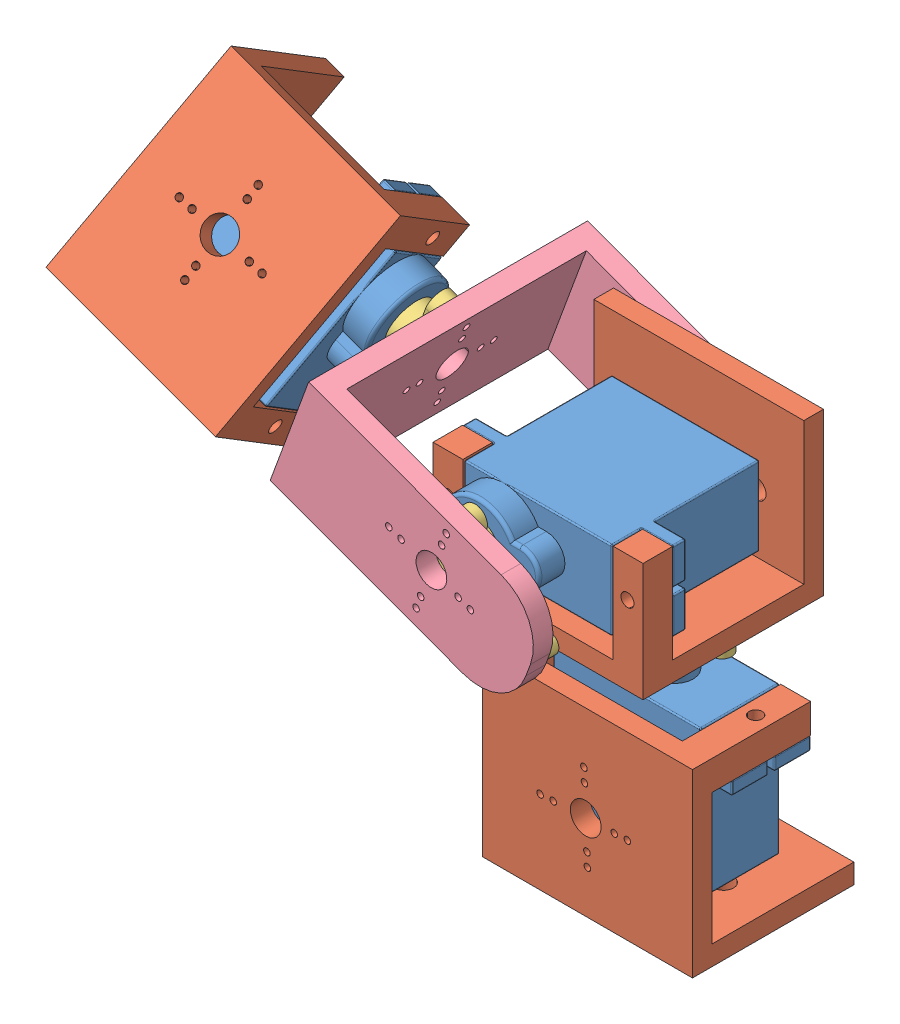
SolidWorks assembly Assem1, configuration Default. Lengths in mm.
Overall size (89.47 82.62 43.13).
10 component instances, 4 part files, 32 mates.
Components (placement in the parent):
- ServoMotor-1: ServoMotor [Valor predeterminado] at (8.0384 16.6646 27.6667) size (32 29 12)
- Body_Bracket-1: Body_Bracket [Default] at (-47.5997 31.1646 40.4918) size (32 24.6 27.5)
- Tower pro micro servo SG90 HORN-1: Tower pro micro servo SG90 HORN [Varsayılan] at (2.7884 29.6646 27.6667) x (0.999158 0 0.041036) z (-0.041036 0 0.999158) size (34.3 4 16.6)
- ServoMotor-2: ServoMotor [Valor predeterminado] at (3.0593 43.1646 35.7218) x (1 0 0) z (0 -1 0) size (32 29 12)
- Head_Bracket-1: Head_Bracket [Default] at (4.3424 15.0129 50.2218) x (0.938532 -0.345191 0) z (0 0 1) size (38.75 16.96 42.5)
- Tower pro micro servo SG90 HORN-2: Tower pro micro servo SG90 HORN [Varsayılan] at (-2.1907 43.1646 48.7218) x (0.935017 -0.354604 0) z (-0.354604 -0.935017 0) size (34.3 4 16.6)
- Tower pro micro servo SG90 HORN-3: Tower pro micro servo SG90 HORN [Varsayılan] at (-25.0551 51.6993 31.4226) x (0 0 -1) z (-0.345191 -0.938532 0) size (34.3 4 16.6)
- ServoMotor-3: ServoMotor [Valor predeterminado] at (-38.6969 52.2692 34.6068) x (-0.274451 -0.746199 0.606517) z (0.209364 0.569236 0.79507) size (32 29 12)
- Body_Bracket-3: Body_Bracket [Default] at (-42.6206 21.4346 39.6667) x (1 0 0) z (0 1 0) size (32 24.6 27.5)
- Body_Bracket-4: Body_Bracket [Default] at (-17.8043 95.2552 13.4221) x (-0.274451 -0.746199 0.606517) z (0.938532 -0.345191 0) size (32 24.6 27.5)
Mates (geometry in assembly coordinates):
- Concentric1: concentric anti-aligned: cylinder of ServoMotor-1 through (2.7884 29.6646 27.6667) axis (0 -1 0) radius 2.25; cylinder of Tower pro micro servo SG90 HORN-1 through (2.7884 27.1646 27.6667) axis (0 1 0) radius 2.3
- Coincident2: coincident anti-aligned: plane of ServoMotor-1 through (2.7884 27.1646 27.6667) normal (0 1 0); plane of Tower pro micro servo SG90 HORN-1 through (2.7884 27.1646 27.6667) normal (0 -1 0)
- Coincident3: coincident anti-aligned: plane of Body_Bracket-1 through (-47.5997 31.1646 40.4918) normal (0 -1 0); plane of Tower pro micro servo SG90 HORN-1 through (2.7884 31.1646 27.6667) normal (0 1 0)
- Distance1: distance = 3 mm anti-aligned: plane of ServoMotor-2 through (-8.1907 37.1646 19.7218) normal (0 -1 0); plane of Body_Bracket-1 through (-47.5997 34.1646 40.4918) normal (0 1 0)
- Distance2: distance = 5 mm aligned: plane of ServoMotor-2 through (3.0593 43.1646 19.7218) normal (0 0 -1); plane of Body_Bracket-1 through (19.0593 41.1646 14.7218) normal (0 0 -1)
- Coincident6: coincident aligned: plane of Body_Bracket-1 through (19.0593 41.1646 40.4918) normal (1 0 0); plane of ServoMotor-2 through (19.0593 49.1646 37.7218) normal (1 0 0)
- Concentric2: concentric aligned: cylinder of ServoMotor-2 through (-2.1907 43.1646 48.7218) axis (0 0 -1) radius 2.25; circle of Tower pro micro servo SG90 HORN-2
- Coincident7: coincident anti-aligned: plane of ServoMotor-2 through (-2.1907 43.1646 46.2218) normal (0 0 1); plane of Tower pro micro servo SG90 HORN-2 through (-2.1907 43.1646 46.2218) normal (0 0 -1)
- Tangent3: tangent aligned: plane of Head_Bracket-1 through (4.3424 15.0129 53.2218) normal (0.938532 -0.345191 0); cylinder of Tower pro micro servo SG90 HORN-2 through (11.2268 38.0761 50.2218) axis (0 0 -1) radius 1.5
- Coincident8: coincident anti-aligned: plane of Head_Bracket-1 through (-32.0298 28.3905 50.2218) normal (-0.938532 0.345191 0); plane of Tower pro micro servo SG90 HORN-3 through (-23.6473 51.1815 31.4226) normal (0.938532 -0.345191 0)
- Coincident10: coincident anti-aligned: plane of Head_Bracket-1 through (4.3424 15.0129 50.2218) normal (0 0 -1); plane of Tower pro micro servo SG90 HORN-2 through (-2.1907 43.1646 50.2218) normal (0 0 1)
- Parallel3: parallel aligned: plane of ServoMotor-1 through (-3.2116 0.6646 33.6667) normal (0 0 1); plane of Body_Bracket-1 through (3.0593 43.1646 42.2218) normal (0 0 1)
- Parallel4: parallel aligned: plane of ServoMotor-1 through (-3.2116 0.6646 33.6667) normal (0 0 1); plane of Body_Bracket-1 through (3.0593 43.1646 42.2218) normal (0 0 1)
- Concentric7: concentric anti-aligned: circle of Body_Bracket-1; circle of Tower pro micro servo SG90 HORN-1
- Concentric8: concentric aligned: circle of Body_Bracket-1; cylinder of Tower pro micro servo SG90 HORN-1 through (7.1347 31.1646 27.8452) axis (0 -1 0) radius 0.5
- Concentric11: concentric aligned: circle of Head_Bracket-1; cylinder of Tower pro micro servo SG90 HORN-2 through (0.061 49.102 50.2218) axis (0 0 -1) radius 0.5
- Concentric12: concentric anti-aligned: circle of Head_Bracket-1; circle of Tower pro micro servo SG90 HORN-2
- Tangent12: tangent aligned: plane of Head_Bracket-1 through (-17.1489 57.2621 150.2218) normal (0.345191 0.938532 0); cylinder of Tower pro micro servo SG90 HORN-3 through (-21.5589 56.8596 31.4226) axis (-0.938532 0.345191 0) radius 1.9
- Coincident11: coincident anti-aligned: plane of Tower pro micro servo SG90 HORN-3 through (-25.0551 51.6993 31.4226) normal (-0.938532 0.345191 0); plane of ServoMotor-3 through (-25.0551 51.6993 31.4226) normal (0.938532 -0.345191 0)
- Concentric14: concentric aligned: circle of Tower pro micro servo SG90 HORN-3; cylinder of ServoMotor-3 through (-25.0551 51.6993 31.4226) axis (-0.938532 0.345191 0) radius 2.25
- Concentric15: concentric aligned: cylinder of Head_Bracket-1 through (-8.3158 52.3085 31.4226) axis (-0.938532 0.345191 0) radius 0.5; cylinder of Tower pro micro servo SG90 HORN-3 through (-21.4553 57.1412 31.4226) axis (-0.938532 0.345191 0) radius 0.5
- Concentric16: concentric aligned: cylinder of Head_Bracket-1 through (-10.5078 46.3488 36.3726) axis (-0.938532 0.345191 0) radius 0.5; cylinder of Tower pro micro servo SG90 HORN-3 through (-23.6473 51.1815 36.3726) axis (-0.938532 0.345191 0) radius 0.5
- Concentric17: concentric aligned: cylinder of Head_Bracket-1 through (-6.8191 44.9199 64.2218) axis (0 0 -1) radius 0.5; cylinder of Tower pro micro servo SG90 HORN-2 through (-6.8191 44.9199 50.2218) axis (0 0 -1) radius 0.5
- Concentric18: concentric aligned: cylinder of Head_Bracket-1 through (-0.6482 47.2319 64.2218) axis (0 0 -1) radius 0.5; cylinder of Tower pro micro servo SG90 HORN-2 through (-0.6482 47.2319 50.2218) axis (0 0 -1) radius 0.5
- Concentric19: concentric aligned: cylinder of Body_Bracket-1 through (-4.1557 41.1646 27.3815) axis (0 -1 0) radius 0.5; cylinder of Tower pro micro servo SG90 HORN-1 through (-4.1557 31.1646 27.3815) axis (0 -1 0) radius 0.5
- Concentric20: concentric aligned: cylinder of Body_Bracket-1 through (2.5996 41.1646 32.2629) axis (0 -1 0) radius 0.5; cylinder of Tower pro micro servo SG90 HORN-1 through (2.5996 31.1646 32.2629) axis (0 -1 0) radius 0.5
- Concentric23: concentric aligned: cylinder of ServoMotor-1 through (-5.5866 18.6646 27.6667) axis (0 -1 0) radius 1; cylinder of Body_Bracket-3 through (-5.5866 28.6646 27.6667) axis (0 -1 0) radius 1
- Concentric24: concentric aligned: cylinder of ServoMotor-1 through (21.6634 18.6646 27.6667) axis (0 -1 0) radius 1; cylinder of Body_Bracket-3 through (21.6634 28.6646 27.6667) axis (0 -1 0) radius 1
- Coincident13: coincident anti-aligned: plane of ServoMotor-1 through (21.6634 18.6646 27.6667) normal (0 1 0); plane of Body_Bracket-3 through (-5.5866 18.6646 27.6667) normal (0 -1 0)
- Concentric25: concentric aligned: cylinder of ServoMotor-3 through (-33.0804 61.7458 26.343) axis (-0.938532 0.345191 0) radius 1; cylinder of Body_Bracket-4 through (-23.6951 58.2939 26.343) axis (-0.938532 0.345191 0) radius 1
- Concentric26: concentric aligned: cylinder of ServoMotor-3 through (-40.5592 41.4119 42.8706) axis (-0.938532 0.345191 0) radius 1; cylinder of Body_Bracket-4 through (-31.1739 37.96 42.8706) axis (-0.938532 0.345191 0) radius 1
- Coincident14: coincident anti-aligned: plane of ServoMotor-3 through (-33.0804 61.7458 26.343) normal (0.938532 -0.345191 0); plane of Body_Bracket-4 through (-33.0804 61.7458 26.343) normal (-0.938532 0.345191 0)
